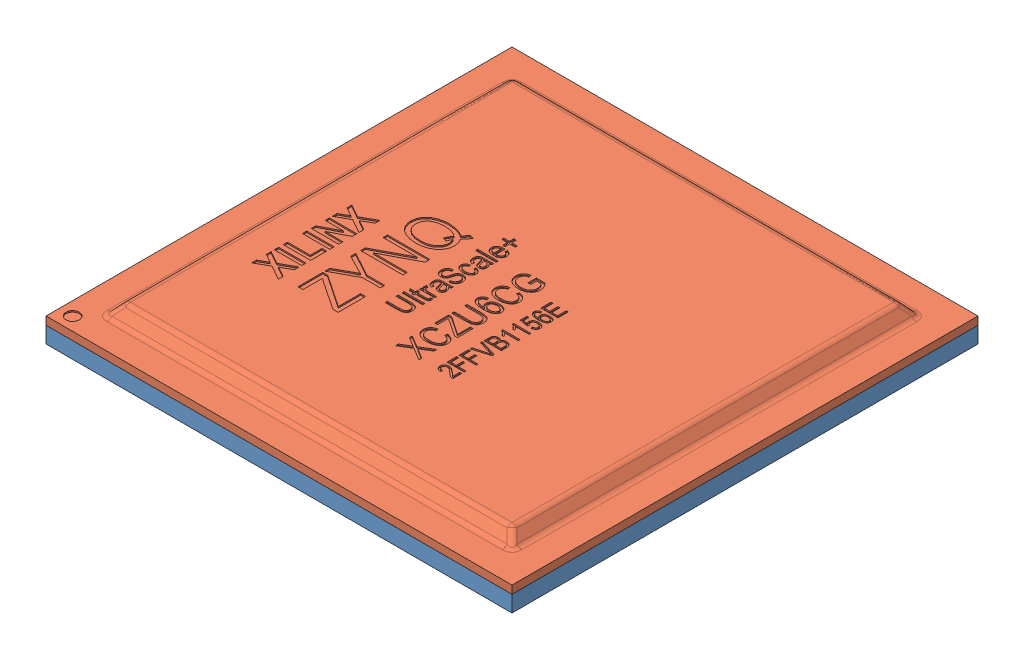
SolidWorks assembly XCZU6CG-2FFVB1156E, configuration Default. Lengths in mm.
Overall size (35 3.22 35).
14 component instances, 3 part files, 15 mates.
Components (placement in the parent):
- Body-1: Body [Default] at (0 0.5 0) size (35 1.22 35)
- Lid-1: Lid [Default] at (0 1.72 0) size (35 1.5 35)
- Bal-1: Bal [Default] at (-16.5 0.25 -16.5) x (1 0 0) z (0 1 0) size (0.7 0.7 0.5)
- Bal-3: Bal [Default] at (-15.5 0.25 -16.5) x (1 0 0) z (0 1 0) size (0.7 0.7 0.5)
- Bal-4: Bal [Default] at (-16.5 0.25 -15.5) x (1 0 0) z (0 1 0) size (0.7 0.7 0.5)
- Bal-5: Bal [Default] at (-16.5 0.25 16.5) x (1 0 0) z (0 -1 0) size (0.7 0.7 0.5)
- Bal-6: Bal [Default] at (-15.5 0.25 16.5) x (1 0 0) z (0 -1 0) size (0.7 0.7 0.5)
- Bal-7: Bal [Default] at (-16.5 0.25 15.5) x (1 0 0) z (0 -1 0) size (0.7 0.7 0.5)
- Bal-8: Bal [Default] at (16.5 0.25 -16.5) x (-1 0 0) z (0 -1 0) size (0.7 0.7 0.5)
- Bal-9: Bal [Default] at (15.5 0.25 -16.5) x (-1 0 0) z (0 -1 0) size (0.7 0.7 0.5)
- Bal-10: Bal [Default] at (16.5 0.25 -15.5) x (-1 0 0) z (0 -1 0) size (0.7 0.7 0.5)
- Bal-11: Bal [Default] at (16.5 0.25 16.5) x (-1 0 0) z (0 1 0) size (0.7 0.7 0.5)
- Bal-12: Bal [Default] at (15.5 0.25 16.5) x (-1 0 0) z (0 1 0) size (0.7 0.7 0.5)
- Bal-13: Bal [Default] at (16.5 0.25 15.5) x (-1 0 0) z (0 1 0) size (0.7 0.7 0.5)
Mates (geometry in assembly coordinates):
- Distance1: distance = 0.5 mm: plane of assembly through (0 0 0) normal (0 1 0); plane of assembly; plane of Body-1 through (0 0.5 0) normal (0 -1 0)
- Coincident2: coincident aligned: plane of Body-1 through (0 0.5 0) normal (0 0 1); plane of assembly through (0 0 0) normal (0 0 1)
- Coincident3: coincident aligned: plane of Body-1 through (0 0.5 0) normal (1 0 0); plane of assembly through (0 0 0) normal (1 0 0)
- Coincident4: coincident anti-aligned: plane of Lid-1 through (0 1.72 0) normal (0 -1 0); plane of Body-1 through (0 1.72 0) normal (0 1 0)
- Coincident5: coincident aligned: plane of Lid-1 through (-17.5 3.22 -17.5) normal (-1 0 0); plane of Body-1 through (-17.5 1.72 17.5) normal (-1 0 0)
- Coincident6: coincident aligned: plane of Body-1 through (-17.5 1.72 17.5) normal (0 0 1); plane of Lid-1 through (-17.5 3.22 17.5) normal (0 0 1)
- Coincident7: coincident anti-aligned: plane of Body-1 through (0 0.5 0) normal (0 -1 0); plane of Bal-1 through (-21.5 0.5 -17.1105) normal (0 1 0)
- Distance2: distance = 16.5 mm: line of Bal-1 through (-16.5 -0.4651 -16.5) axis (0 1 0); plane of assembly through (0 0 0) normal (0 0 1)
- Distance3: distance = 16.5 mm: line of Bal-1 through (-16.5 -0.4651 -16.5) axis (0 1 0); plane of assembly through (0 0 0) normal (1 0 0)
- Coincident10: coincident anti-aligned: plane of Body-1 through (0 0.5 0) normal (0 -1 0); plane of Bal-4 through (-21.5 0.5 -16.1105) normal (0 1 0)
- Coincident11: coincident anti-aligned: plane of Body-1 through (0 0.5 0) normal (0 -1 0); plane of Bal-3 through (-20.5 0.5 -17.1105) normal (0 1 0)
- Distance4: distance = 15.5 mm: line of Bal-4 through (-16.5 -0.4651 -15.5) axis (0 1 0); plane of assembly through (0 0 0) normal (0 0 1)
- Distance5: distance = 16.5 mm: line of Bal-4 through (-16.5 -0.4651 -15.5) axis (0 1 0); plane of assembly through (0 0 0) normal (1 0 0)
- Distance6: distance = 15.5 mm: line of Bal-3 through (-15.5 -0.4651 -16.5) axis (0 1 0); plane of assembly through (0 0 0) normal (1 0 0)
- Distance7: distance = 16.5 mm: line of Bal-3 through (-15.5 -0.4651 -16.5) axis (0 1 0); plane of assembly through (0 0 0) normal (0 0 1)
